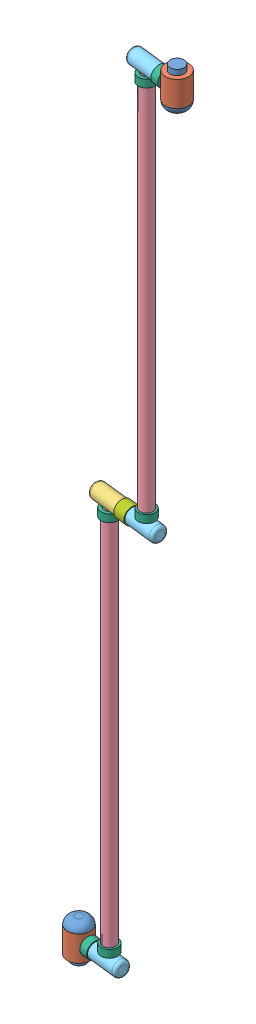
SolidWorks assembly RoboArmV2, configuration Default. Lengths in mm.
Overall size (1810.25 10888.86 535.82).
17 component instances, 7 part files, 37 mates.
Components (placement in the parent):
- Part1_1-1: Part1_1 [Default] at (158.0569 -59.172 446.4984) size (300 500 300)
- Part1_2-1: Part1_2 [Default] at (158.0569 -59.172 446.4984) x (0.114502 0 -0.993423) z (0.993423 0 0.114502) size (300 330 500)
- Part1_1-2: Part1_1 [Default] at (1598.5203 10829.6885 612.5258) x (0.87718 0 0.480162) z (0.480162 0 -0.87718) size (300 500 300)
- Part1_2-2: Part1_2 [Default] at (1598.5203 10829.6885 612.5258) x (0.114502 0 -0.993423) z (-0.993423 0 -0.114502) size (300 330 500)
- Part2-1: Part2 [Default] at (1052.1376 5385.2582 549.5499) x (0.114502 0 -0.993423) z (0 1 0) size (195 650 195)
- Part3-1: Part3 [Default] at (605.0972 190.2582 498.0242) x (0.99976 0 0.021928) z (-0.021928 0 0.99976) size (165 5195 165)
- Part4-1: Part4 [Default] at (1598.5203 10580.2582 612.5258) x (0.114502 0 -0.993423) z (0 1 0) size (195 400 195)
- MotorJoint-1: MotorJoint [Default] at (1151.4799 10482.7582 561.0001) x (0.854518 0 0.519422) z (0.519422 0 -0.854518) size (215 100 215)
- Part4-2: Part4 [Default] at (704.4395 5385.2582 509.4743) x (0.114502 0 -0.993423) z (0 -1 0) size (195 400 195)
- Part4-3: Part4 [Default] at (158.0569 190.2582 446.4984) x (0.114502 0 -0.993423) z (0 -1 0) size (195 400 195)
- MotorJoint-2: MotorJoint [Default] at (1151.4799 5582.7582 561.0001) x (0.854518 0 0.519422) z (0.519422 0 -0.854518) size (215 100 215)
- MotorJoint-3: MotorJoint [Default] at (307.0703 190.2582 463.6737) x (-0.029978 -0.965119 0.26009) z (-0.110508 0.261812 0.958771) size (215 100 215)
- MotorJoint-4: MotorJoint [Default] at (605.0972 287.7582 498.0242) x (0.99976 0 0.021928) z (-0.021928 0 0.99976) size (215 100 215)
- MotorJoint-5: MotorJoint [Default] at (605.0972 5187.7582 498.0242) x (0.99976 0 0.021928) z (-0.021928 0 0.99976) size (215 100 215)
- MotorJoint-6: MotorJoint [Default] at (1449.5068 10580.2582 595.3506) x (0.056324 0.870648 -0.488672) z (-0.099691 0.491907 0.864922) size (215 100 215)
- MotorJoint2-1: MotorJoint2 [Default] at (952.7953 5385.2582 538.0997) x (-0.112268 0.196549 0.974045) z (-0.022505 -0.980494 0.195256) size (215 150 215)
- Part3-2: Part3 [Default] at (1151.4799 10580.2582 561.0001) x (-0.854518 0 -0.519422) z (-0.519422 0 0.854518) size (165 5195 165)
Mates (geometry in assembly coordinates):
- Concentric1: concentric aligned: cylinder of Part1_1-1 through (158.0569 340.828 446.4984) axis (0 -1 0) radius 90; cylinder of Part1_2-1 through (158.0569 340.828 446.4984) axis (0 -1 0) radius 90
- Coincident1: coincident anti-aligned: plane of Part1_1-1 through (158.0569 340.828 446.4984) normal (0 -1 0); plane of Part1_2-1 through (158.0569 340.828 446.4984) normal (0 1 0)
- Coincident2: coincident anti-aligned: plane of Part4-3 through (406.4126 190.2582 475.1238) normal (-0.993423 0 -0.114502); plane of MotorJoint-3 through (406.4126 190.2582 475.1238) normal (0.993423 0 0.114502)
- Concentric3: concentric anti-aligned: cylinder of Part1_2-1 through (505.7549 190.2582 486.574) axis (-0.993423 0 -0.114502) radius 67.5; cylinder of MotorJoint-3 through (307.0703 190.2582 463.6737) axis (0.993423 0 0.114502) radius 67.5
- Coincident3: coincident anti-aligned: plane of Part1_2-1 through (505.7549 190.2582 486.574) normal (0.993423 0 0.114502); plane of Part4-3 through (505.7549 190.2582 486.574) normal (-0.993423 0 -0.114502)
- Concentric4: concentric aligned: cylinder of Part1_2-1 through (505.7549 190.2582 486.574) axis (-0.993423 0 -0.114502) radius 67.5; cylinder of Part4-3 through (505.7549 190.2582 486.574) axis (-0.993423 0 -0.114502) radius 67.5
- Coincident4: coincident anti-aligned: plane of Part3-1 through (605.0972 387.7582 498.0242) normal (0 -1 0); plane of MotorJoint-4 through (605.0972 387.7582 498.0242) normal (0 1 0)
- Concentric5: concentric anti-aligned: cylinder of Part3-1 through (605.0972 387.7582 498.0242) axis (0 -1 0) radius 67.5; cylinder of MotorJoint-4 through (605.0972 287.7582 498.0242) axis (0 1 0) radius 67.5
- Coincident6: coincident anti-aligned: plane of MotorJoint-1 through (1151.4799 10382.7582 561.0001) normal (0 -1 0); plane of Part3-2 through (1151.4799 10382.7582 561.0001) normal (0 1 0)
- Concentric7: concentric anti-aligned: cylinder of MotorJoint-1 through (1151.4799 10482.7582 561.0001) axis (0 -1 0) radius 67.5; cylinder of Part3-2 through (1151.4799 10382.7582 561.0001) axis (0 1 0) radius 67.5
- Coincident7: coincident anti-aligned: plane of MotorJoint-2 through (1151.4799 5582.7582 561.0001) normal (0 1 0); plane of Part3-2 through (1151.4799 5582.7582 561.0001) normal (0 -1 0)
- Concentric8: concentric aligned: cylinder of MotorJoint-2 through (1151.4799 5582.7582 561.0001) axis (0 -1 0) radius 67.5; cylinder of Part3-2 through (1151.4799 5582.7582 561.0001) axis (0 -1 0) radius 67.5
- Coincident8: coincident anti-aligned: plane of Part3-1 through (605.0972 5187.7582 498.0242) normal (0 1 0); plane of MotorJoint-5 through (605.0972 5187.7582 498.0242) normal (0 -1 0)
- Concentric9: concentric aligned: cylinder of Part3-1 through (605.0972 5187.7582 498.0242) axis (0 1 0) radius 67.5; cylinder of MotorJoint-5 through (605.0972 5187.7582 498.0242) axis (0 1 0) radius 67.5
- Coincident9: coincident anti-aligned: plane of Part2-1 through (803.7818 5385.2582 520.9245) normal (0.993423 0 0.114502); plane of MotorJoint2-1 through (803.7818 5385.2582 520.9245) normal (-0.993423 0 -0.114502)
- Concentric10: concentric anti-aligned: cylinder of Part2-1 through (803.7818 5385.2582 520.9245) axis (0.993423 0 0.114502) radius 67.5; cylinder of MotorJoint2-1 through (952.7953 5385.2582 538.0997) axis (-0.993423 0 -0.114502) radius 67.5
- Coincident10: coincident anti-aligned: plane of Part1_1-2 through (1598.5203 10429.6885 612.5258) normal (0 1 0); plane of Part1_2-2 through (1598.5203 10429.6885 612.5258) normal (0 -1 0)
- Concentric11: concentric aligned: cylinder of Part1_1-2 through (1598.5203 10429.6885 612.5258) axis (0 1 0) radius 90; cylinder of Part1_2-2 through (1598.5203 10429.6885 612.5258) axis (0 1 0) radius 90
- Coincident11: coincident anti-aligned: plane of Part3-1 through (605.0972 190.2582 498.0242) normal (0 -1 0); plane of Part4-3 through (605.0972 190.2582 498.0242) normal (0 1 0)
- Concentric12: concentric aligned: cylinder of Part3-1 through (605.0972 387.7582 498.0242) axis (0 -1 0) radius 67.5; cylinder of Part4-3 through (605.0972 287.7582 498.0242) axis (0 -1 0) radius 67.5
- Coincident12: coincident anti-aligned: plane of Part4-2 through (952.7953 5385.2582 538.0997) normal (-0.993423 0 -0.114502); plane of MotorJoint2-1 through (952.7953 5385.2582 538.0997) normal (0.993423 0 0.114502)
- Concentric13: concentric anti-aligned: cylinder of Part2-1 through (803.7818 5385.2582 520.9245) axis (0.993423 0 0.114502) radius 67.5; cylinder of Part4-2 through (1052.1376 5385.2582 549.5499) axis (-0.993423 0 -0.114502) radius 67.5
- Coincident13: coincident anti-aligned: plane of Part2-1 through (605.0972 5385.2582 498.0242) normal (0 -1 0); plane of Part3-1 through (605.0972 5385.2582 498.0242) normal (0 1 0)
- Concentric14: concentric aligned: cylinder of Part2-1 through (605.0972 5287.7582 498.0242) axis (0 1 0) radius 67.5; cylinder of Part3-1 through (605.0972 5187.7582 498.0242) axis (0 1 0) radius 67.5
- Coincident14: coincident anti-aligned: plane of Part4-2 through (1151.4799 5385.2582 561.0001) normal (0 1 0); plane of Part3-2 through (1151.4799 5385.2582 561.0001) normal (0 -1 0)
- Concentric15: concentric aligned: cylinder of Part4-2 through (1151.4799 5482.7582 561.0001) axis (0 -1 0) radius 67.5; cylinder of Part3-2 through (1151.4799 5582.7582 561.0001) axis (0 -1 0) radius 67.5
- Coincident15: coincident anti-aligned: plane of Part4-1 through (1151.4799 10580.2582 561.0001) normal (0 -1 0); plane of Part3-2 through (1151.4799 10580.2582 561.0001) normal (0 1 0)
- Concentric16: concentric aligned: cylinder of Part4-1 through (1151.4799 10482.7582 561.0001) axis (0 1 0) radius 67.5; cylinder of Part3-2 through (1151.4799 10382.7582 561.0001) axis (0 1 0) radius 67.5
- Concentric17: concentric anti-aligned: cylinder of Part1_2-2 through (1250.8222 10580.2582 572.4502) axis (0.993423 0 0.114502) radius 67.5; cylinder of MotorJoint-6 through (1449.5068 10580.2582 595.3506) axis (-0.993423 0 -0.114502) radius 67.5
- Coincident16: coincident anti-aligned: plane of Part4-1 through (1350.1645 10580.2582 583.9004) normal (0.993423 0 0.114502); plane of MotorJoint-6 through (1350.1645 10580.2582 583.9004) normal (-0.993423 0 -0.114502)
- Coincident17: coincident anti-aligned: plane of Part1_2-2 through (1250.8222 10580.2582 572.4502) normal (-0.993423 0 -0.114502); plane of Part4-1 through (1250.8222 10580.2582 572.4502) normal (0.993423 0 0.114502)
- Concentric18: concentric aligned: cylinder of Part1_2-2 through (1250.8222 10580.2582 572.4502) axis (0.993423 0 0.114502) radius 67.5; cylinder of Part4-1 through (1250.8222 10580.2582 572.4502) axis (0.993423 0 0.114502) radius 67.5
- Parallel1: parallel aligned: cylinder of Part1_2-1 through (158.0569 440.828 446.4984) axis (0 -1 0) radius 150; cylinder of Part3-1 through (605.0972 5385.2582 498.0242) axis (0 -1 0) radius 82.5
- Parallel2: parallel aligned: cylinder of Part4-2 through (1350.1645 5385.2582 583.9004) axis (-0.993423 0 -0.114502) radius 97.5; cylinder of Part4-3 through (803.7818 190.2582 520.9245) axis (-0.993423 0 -0.114502) radius 97.5
- Parallel3: parallel anti-aligned: cylinder of Part3-1 through (605.0972 5385.2582 498.0242) axis (0 -1 0) radius 82.5; cylinder of Part3-2 through (1151.4799 5385.2582 561.0001) axis (0 1 0) radius 82.5
- Parallel4: parallel aligned: cylinder of Part2-1 through (406.4126 5385.2582 475.1238) axis (0.993423 0 0.114502) radius 97.5; cylinder of Part4-1 through (952.7953 10580.2582 538.0997) axis (0.993423 0 0.114502) radius 97.5
- Parallel5: parallel aligned: cylinder of Part1_2-2 through (1598.5203 10329.6885 612.5258) axis (0 1 0) radius 150; cylinder of Part3-2 through (1151.4799 5385.2582 561.0001) axis (0 1 0) radius 82.5
